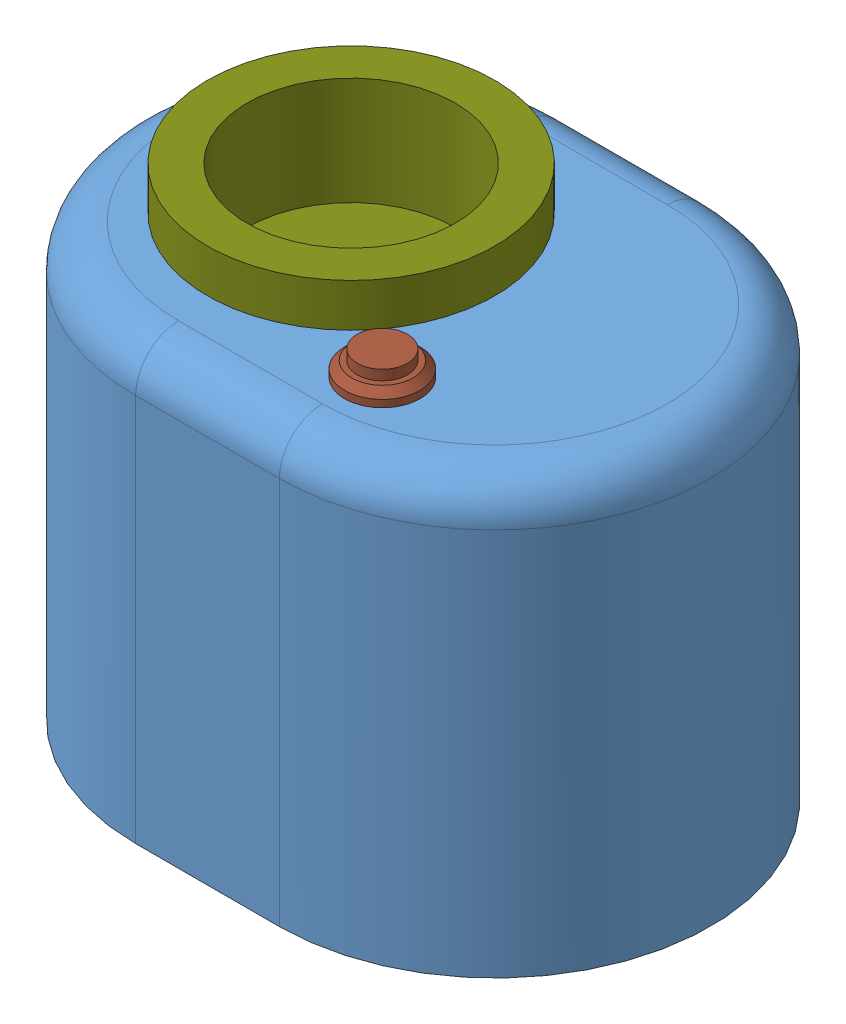
SolidWorks assembly 风扇装配, configuration 默认. Lengths in mm.
Overall size (80 67 60).
19 component instances, 16 part files, 47 mates.
Components (placement in the parent):
- 摇头底座装配体-1: 摇头底座装配体 [默认] at (-5.2179 0.5756 0) size (80 60 60)
  - 风扇底座-1: 风扇底座 [默认] at (-9.9157 -30.801 80) size (80 60 60)
  - Rolling bearings 619-5 GB 276-94-1: Rolling bearings 619-5 GB 276-94 [Rolling bearings 619-5 GB 276-94] at (-9.9157 -2.801 80) x (0 1 0) z (0.662295 0 0.749243) size (4 13 13)
  - Rolling bearings 619-9 GB 276-94-1: Rolling bearings 619-9 GB 276-94 [Rolling bearings 619-9 GB 276-94] at (-9.9157 11.199 80) x (0 1 0) z (-0.421672 0 0.906748) size (6 20 20)
  - 减速电机-1: 减速电机 [默认] at (21.0843 0.399 80) x (-1 0 0) z (0 0 -1) size (32 35.4 47)
- M3防松螺母-2: M3防松螺母 [默认] at (-0.1573 -6.8254 85.9682) x (0.438566 0 0.898699) z (0 -1 0) size (5.96 6.19 3.9)
- 连杆-2: 连杆 [默认] at (-0.1573 -12.2254 85.9682) x (-0.802372 0 0.596825) z (0 -1 0) size (33 10 6)
- M4防松螺母-3: M4防松螺母 [默认] at (-15.1336 -12.1254 80) x (0.999986 0 -0.005218) z (0 1 0) size (7.59 7.89 4.99)
- M3螺丝-3: M3螺丝 [默认] at (-0.1573 -18.2254 85.9682) x (0.44721 0 0.894429) z (0.894429 0 -0.44721) size (7 14.5 7)
- 轴肩螺丝-1: 轴肩螺丝 [默认] at (-15.1336 21.2746 80) x (0.945832 0 0.324656) z (-0.324656 0 0.945832) size (9 36.5 9)
- 零件1^风扇装配-1: 零件1^风扇装配 [默认] at (-15.1336 21.2746 80) x (0.324656 0 -0.945832) z (0.945832 0 0.324656) size (12.8 8.88 12.8) (virtual)
- M3螺丝-4: M3螺丝 [默认] at (-18.6119 -18.2254 99.6952) x (-0.507551 0 -0.861622) z (-0.861622 0 0.507551) size (7 14.5 7)
- M3防松螺母-3: M3防松螺母 [默认] at (-18.6119 -5.8254 99.6952) x (0.935778 0 0.35259) z (0 -1 0) size (5.96 6.19 3.9)
- 按钮-1: 按钮 [默认] at (5.8033 33.1746 96.594) x (0 -1 0) z (-0.337611 0 -0.941286) size (21.9 10.5 10.5)
- M8薄螺母-1: M8薄螺母 [默认] at (5.8033 25.5746 96.594) x (1 0 0) z (0 1 0) size (10.07 11.43 2.2)
- 曲柄-1: 曲柄 [默认] at (7.8664 -12.2254 80) x (-0.802372 0 0.596825) z (0 1 0) size (20 10 7)
- 摇杆-1: 摇杆 [默认] at (-15.1336 -4.2254 80) x (-0.173913 0 0.984761) z (0 -1 0) size (32 12 10)
- 底盖-1: 底盖 [默认] at (-15.1336 -28.2255 80) x (-1 0 0) z (0 -1 0) size (76 56 2)
- 风扇摇头底座-1: 风扇摇头底座 [默认] at (-15.1336 9.7746 80) x (-0.173913 0 0.984761) z (-0.984761 0 -0.173913) size (40 27 40)
Mates (geometry in assembly coordinates):
- 同心7: concentric: cylinder of ? through (4.9042 -12.2254 70.4488) axis (0 -1 0) radius 2.075; circle of ?
- 重合12: coincident: plane of ? through (4.9042 -9.2254 70.4488) normal (0 -1 0); circle of ?
- 同心15: concentric: circle of ?; circle of ?
- 同心16: concentric: circle of ?; circle of ?
- 重合19: coincident: plane of ? through (7.8664 -12.2254 80) normal (0 -1 0); plane of ? through (4.9042 -12.2254 70.4488) normal (0 1 0)
- 同心17: concentric: circle of ?; cylinder of M4防松螺母-3 through (-15.1336 -9.2254 80) axis (0 1 0) radius 1.65
- 同心18: concentric: cylinder of assembly; cylinder of assembly; cylinder of 连杆-2 through (-0.1573 -12.2254 85.9682) axis (0 1 0) radius 3.75; cylinder of M3螺丝-3 through (-0.1573 -3.7254 85.9682) axis (0 1 0) radius 3.5
- 重合22: coincident: plane of assembly; plane of assembly; plane of 连杆-2 through (2.8516 -14.7254 83.7302) normal (0 -1 0); plane of M3螺丝-3 through (-1.7225 -14.7254 82.8377) normal (0 1 0)
- 同心19: concentric: circle of ?; circle of 轴肩螺丝-1
- 在位1: in place: plane of ? through (-15.1336 21.2746 80) normal (0.397804 0 -0.917471); plane of ? through (-15.1336 21.2746 80) normal (0.397804 0 -0.917471); moOrthogonalPlaneRef_w of ? through (-15.1336 21.2746 80) normal (0.397804 0 -0.917471); plane of ? through (-15.1336 21.2746 80) normal (0 1 0); plane of ? through (-15.1336 21.2746 80) normal (0.397804 0 -0.917471); plane of ? through (-15.1336 21.2746 80) normal (-0.917471 0 -0.397804); plane of 轴肩螺丝-1 through (-15.1336 21.2746 80) normal (0.945832 0 0.324656); unknown of 零件1^风扇装配-1
- 重合24: coincident: plane of assembly; plane of assembly; plane of 轴肩螺丝-1; plane of 零件1^风扇装配-1
- 重合25: coincident: plane of assembly; plane of assembly; moOrthogonalPlaneRef_w of 轴肩螺丝-1; plane of 零件1^风扇装配-1 through (-15.1336 21.2746 80) normal (0 1 0)
- 重合26: coincident: plane of assembly; plane of assembly; moOrthogonalPlaneRef_w of 轴肩螺丝-1; plane of 零件1^风扇装配-1 through (-15.1336 21.2746 80) normal (0.324656 0 -0.945832)
- 同心20: concentric: cylinder of assembly; cylinder of assembly; cylinder of 连杆-2 through (-18.6119 -12.2254 99.6952) axis (0 1 0) radius 3.75; cylinder of M3螺丝-4 through (-18.6119 -3.7254 99.6952) axis (0 1 0) radius 3.5
- 重合27: coincident: plane of assembly; plane of assembly; plane of 连杆-2 through (-15.603 -14.7254 97.4571) normal (0 -1 0); plane of M3螺丝-4 through (-16.8354 -14.7254 102.7109) normal (0 1 0)
- 平行6: parallel: plane of ? through (-3.0406 -8.2254 94.0712) normal (0.647208 0 -0.762313); unknown of ?
- 重合30: coincident: plane of ? through (-15.1336 -8.2254 80) normal (0 1 0); plane of ? through (0.1127 -8.2254 92.9442) normal (0 -1 0)
- 同心23: concentric: circle of assembly; circle of assembly; circle of M3螺丝-4; circle of M3防松螺母-3
- 重合31: coincident: plane of assembly; circle of assembly; plane of 摇头底座装配体-1/风扇底座-1 through (-15.1336 29.7746 80) normal (0 1 0); circle of 按钮-1
- 同心24: concentric: circle of assembly; cylinder of assembly; circle of 按钮-1; cylinder of M8薄螺母-1 through (5.8033 27.7746 96.594) axis (0 -1 0) radius 3.35
- 重合33: coincident: plane of assembly; plane of assembly; plane of 摇头底座装配体-1/风扇底座-1 through (-15.1336 27.7746 80) normal (0 -1 0); plane of M8薄螺母-1 through (5.8033 27.7746 96.594) normal (0 1 0)
- 同心25: concentric: circle of assembly; circle of assembly; circle of 摇头底座装配体-1/风扇底座-1; circle of 按钮-1
- 平行7: parallel: plane of ? through (5.8961 -9.2254 73.6471) normal (-0.734095 0 -0.679047); unknown of ?
- 平行8: parallel: plane of ? through (-11.1648 -9.2254 78.5814) normal (-0.983787 0 -0.179342); plane of M4防松螺母-3 through (-12.0527 -9.2254 82.6157) normal (0.983787 0 0.179342)
- 重合36: coincident: plane of ? through (0 -9.2254 0) normal (0 -1 0); plane of M4防松螺母-3 through (-15.1336 -9.2254 80) normal (0 1 0)
- 重合37: coincident: plane of assembly; plane of assembly; plane of 摇头底座装配体-1/减速电机-1 through (7.8664 -9.2254 80) normal (0 -1 0); plane of 曲柄-1 through (7.8664 -9.2254 80) normal (0 1 0)
- 同心26: concentric: circle of assembly; circle of assembly; circle of 摇头底座装配体-1/减速电机-1; circle of 曲柄-1
- 重合39: coincident: plane of assembly; plane of assembly; plane of 连杆-2 through (-0.1573 -12.2254 85.9682) normal (0 1 0); plane of 曲柄-1 through (7.8664 -12.2254 80) normal (0 -1 0)
- 同心27: concentric: circle of assembly; circle of assembly; circle of 连杆-2; circle of 曲柄-1
- 重合40: coincident: plane of assembly; plane of assembly; plane of M3防松螺母-2 through (-0.1573 -9.2254 85.9682) normal (0 -1 0); plane of 曲柄-1 through (7.8664 -9.2254 80) normal (0 1 0)
- 平行9: parallel: plane of assembly; plane of assembly; plane of M3防松螺母-2 through (2.7579 -9.2254 87.2272) normal (0.596825 0 0.802372); plane of 曲柄-1 through (0.2301 -9.2254 89.2944) normal (-0.596825 0 -0.802372)
- 同心29: concentric: cylinder of assembly; circle of assembly; cylinder of M3防松螺母-2 through (-0.1573 -9.2254 85.9682) axis (0 -1 0) radius 1.25; circle of M3螺丝-3
- 重合42: coincident: plane of assembly; plane of assembly; plane of M3防松螺母-3 through (-18.6119 -8.2254 99.6952) normal (0 -1 0); plane of 摇杆-1 through (-15.1336 -8.2254 80) normal (0 1 0)
- 重合45: coincident: plane of assembly; plane of assembly; plane of 摇头底座装配体-1/Rolling bearings 619-5 GB 276-94-1 through (-18.0057 -4.2254 82.5388) normal (0 -1 0); plane of 摇杆-1 through (-15.1336 -4.2254 80) normal (0 1 0)
- 平行12: parallel: plane of assembly; plane of assembly; plane of M3防松螺母-3 through (-16.1799 -8.2254 101.737) normal (0.341767 0 0.939785); plane of 摇杆-1 through (-19.1942 -8.2254 102.9928) normal (-0.341767 0 -0.939785)
- 同心30: concentric: circle of assembly; circle of assembly; circle of 连杆-2; circle of 摇杆-1
- 同心32: concentric: circle of assembly; circle of assembly; circle of 轴肩螺丝-1; circle of 摇杆-1
- 同心33: concentric: circle of assembly; circle of assembly; circle of 轴肩螺丝-1; circle of 零件1^风扇装配-1
- 重合51: coincident: plane of ? through (-17.2167 17.7746 81.3823) normal (0 1 0); plane of 轴肩螺丝-1 through (-19.3898 17.7746 78.539) normal (0 -1 0)
- 在位2: in place: plane of 摇头底座装配体-1/风扇底座-1 through (-15.1336 -28.2255 80) normal (0 -1 0); plane of ? through (0 -28.2255 0) normal (0 -1 0); plane of 摇头底座装配体-1/风扇底座-1 through (-15.1336 -28.2255 80) normal (0 -1 0); plane of ? through (0 -28.2255 0) normal (0 0 -1); plane of 摇头底座装配体-1/风扇底座-1 through (-15.1336 -28.2255 80) normal (0 -1 0); plane of ? through (0 -28.2255 0) normal (-1 0 0); plane of 摇头底座装配体-1/风扇底座-1 through (-15.1336 -28.2255 80) normal (0 -1 0); unknown of 底盖-1
- 重合52: coincident: plane of assembly; plane of assembly; plane of 摇头底座装配体-1/风扇底座-1; plane of 底盖-1
- 重合53: coincident: plane of assembly; plane of assembly; moOrthogonalPlaneRef_w of 摇头底座装配体-1/风扇底座-1 through (-15.1336 -28.2255 80) normal (0 0 -1); plane of 底盖-1 through (-15.1336 -28.2255 80) normal (0 0 -1)
- 重合54: coincident: plane of assembly; plane of assembly; moOrthogonalPlaneRef_w of 摇头底座装配体-1/风扇底座-1 through (-15.1336 -28.2255 80) normal (1 0 0); plane of 底盖-1 through (-15.1336 -28.2255 80) normal (-1 0 0)
- 重合60: coincident: plane of assembly; plane of assembly; plane of 摇头底座装配体-1/Rolling bearings 619-9 GB 276-94-1 through (-19.214 14.7746 78.1025) normal (0 1 0); plane of 风扇摇头底座-1 through (-14.0032 14.7746 73.5991) normal (0 -1 0)
- 同心34: concentric: circle of assembly; circle of assembly; circle of 轴肩螺丝-1; circle of 风扇摇头底座-1
- 同心35: concentric: circle of assembly; circle of assembly; circle of 摇头底座装配体-1/风扇底座-1; circle of 风扇摇头底座-1
- 平行20: parallel: plane of assembly; plane of assembly; plane of 摇杆-1 through (-15.1336 -4.2254 80) normal (-0.173913 0 0.984761); plane of 风扇摇头底座-1 through (-15.1336 9.7746 80) normal (-0.173913 0 0.984761)
